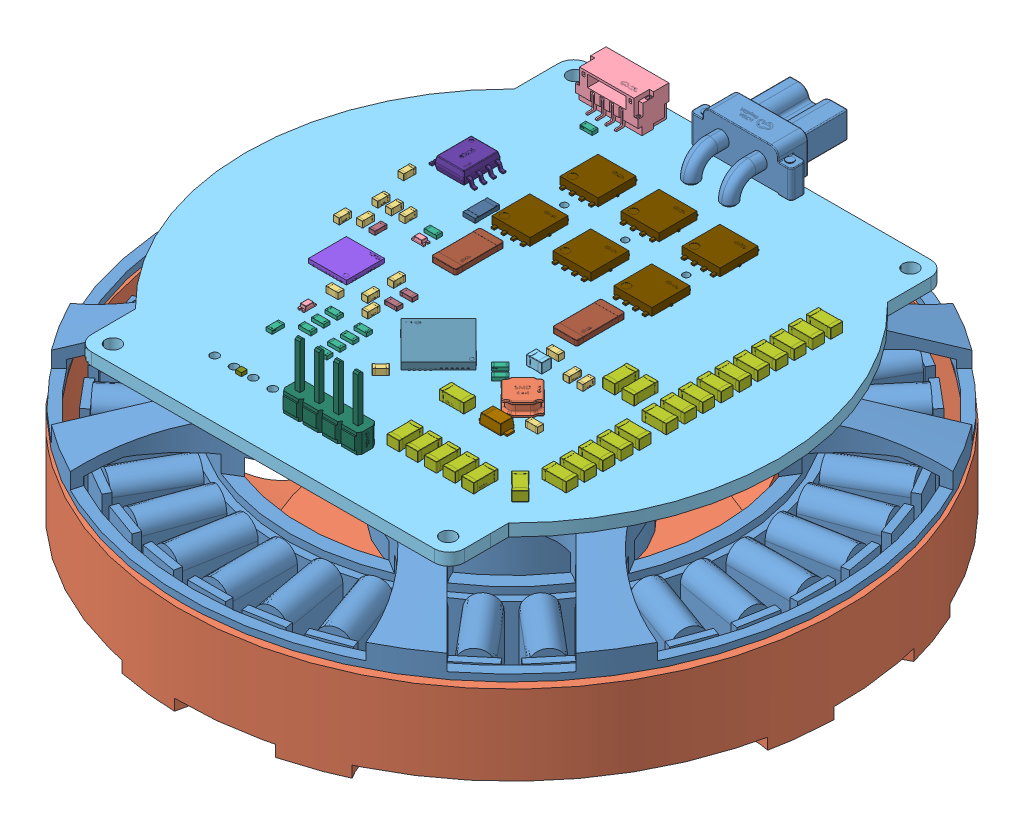
SolidWorks assembly 8108_brushless, configuration Default. Lengths in mm.
Overall size (121.93 40.03 121.93).
306 component instances, 23 part files, 3 mates.
Components (placement in the parent):
- 8108_roter-1: 8108_roter [Default] at (32.6545 40.9666 69.698) size (86.5 19.3 86.5)
- 8108_magnet shaft-1: 8108_magnet shaft [Default] at (32.6545 40.2666 69.698) x (-0.784297 0 -0.620385) z (-0.620385 0 0.784297) size (86.8 25.3 86.8)
- bldc_controller_board.step-1: bldc_controller_board.step [Default] at (32.6609 51.6569 69.7006) x (0.999996 0 -0.002863) z (0 1 0) size (69.98 72.92 11.54)
  - MX0O-C1.step-1: MX0O-C1.step [Default] at (-12.954 -10.287 1.6001) size (1.6 0.8 0.8)
    - C0603.step-1: C0603.step [Default] at origin size (1.6 0.8 0.8)
      - SOLID.step-1: SOLID.step [Default] at origin size (1.6 0.8 0.8)
  - MX0O-C2.step-1: MX0O-C2.step [Default] at (-20.955 -1.27 1.6001) x (0 -1 0) z (0 0 1) size (1.6 0.8 0.8)
    - C0603.step-1: C0603.step [Default] at origin size (1.6 0.8 0.8)
      - SOLID.step-1: SOLID.step [Default] at origin size (1.6 0.8 0.8)
  - MX0O-C8.step-1: MX0O-C8.step [Default] at (8.636 -2.921 1.6001) size (1.6 0.8 0.8)
    - C0603.step-1: C0603.step [Default] at origin size (1.6 0.8 0.8)
      - SOLID.step-1: SOLID.step [Default] at origin size (1.6 0.8 0.8)
  - MX0O-C9.step-1: MX0O-C9.step [Default] at (-8.382 -10.16 1.6001) x (0 -1 0) z (0 0 1) size (1.6 0.8 0.8)
    - C0603.step-1: C0603.step [Default] at origin size (1.6 0.8 0.8)
      - SOLID.step-1: SOLID.step [Default] at origin size (1.6 0.8 0.8)
  - MX0O-C10.step-1: MX0O-C10.step [Default] at (-1.016 -16.256 1.6001) x (0.707107 0.707107 0) z (0 0 1) size (1.6 0.8 0.8)
    - C0603.step-1: C0603.step [Default] at origin size (1.6 0.8 0.8)
      - SOLID.step-1: SOLID.step [Default] at origin size (1.6 0.8 0.8)
  - MX0O-C12.step-1: MX0O-C12.step [Default] at (15.494 -12.573 1.6001) size (1.6 0.8 0.8)
    - C0603.step-1: C0603.step [Default] at origin size (1.6 0.8 0.8)
      - SOLID.step-1: SOLID.step [Default] at origin size (1.6 0.8 0.8)
  - MX0O-C13.step-1: MX0O-C13.step [Default] at (12.239 -4.312 1.6001) x (0 -1 0) z (0 0 1) size (1.6 0.8 0.8)
    - C0603.step-1: C0603.step [Default] at origin size (1.6 0.8 0.8)
      - SOLID.step-1: SOLID.step [Default] at origin size (1.6 0.8 0.8)
  - MX0O-C14.step-1: MX0O-C14.step [Default] at (14.035 -4.3125 1.6001) x (0 -1 0) z (0 0 1) size (1.6 0.8 0.8)
    - C0603.step-1: C0603.step [Default] at origin size (1.6 0.8 0.8)
      - SOLID.step-1: SOLID.step [Default] at origin size (1.6 0.8 0.8)
  - MX0O-C55.step-1: MX0O-C55.step [Default] at (-21.717 8.001 1.6001) x (0 1 0) z (0 0 1) size (1.6 0.8 0.8)
    - C0603.step-1: C0603.step [Default] at origin size (1.6 0.8 0.8)
      - SOLID.step-1: SOLID.step [Default] at origin size (1.6 0.8 0.8)
  - MX0O-U11.step-1: MX0O-U11.step [Default] at (-18.542 3.175 1.6001) x (0 1 0) z (0 0 1) size (1.6 0.8 0.8)
    - C0603.step-1: C0603.step [Default] at origin size (1.6 0.8 0.8)
      - SOLID.step-1: SOLID.step [Default] at origin size (1.6 0.8 0.8)
  - MX0O-U12.step-1: MX0O-U12.step [Default] at (-16.764 3.175 1.6001) x (0 -1 0) z (0 0 1) size (1.6 0.8 0.8)
    - C0603.step-1: C0603.step [Default] at origin size (1.6 0.8 0.8)
      - SOLID.step-1: SOLID.step [Default] at origin size (1.6 0.8 0.8)
  - MX0O-C57.step-1: MX0O-C57.step [Default] at (-10.16 -8.382 1.6001) x (0 -1 0) z (0 0 1) size (1.6 0.8 0.8)
    - C0603.step-1: C0603.step [Default] at origin size (1.6 0.8 0.8)
      - SOLID.step-1: SOLID.step [Default] at origin size (1.6 0.8 0.8)
  - MX0O-C58.step-1: MX0O-C58.step [Default] at (-10.16 -4.953 1.6001) x (0 -1 0) z (0 0 1) size (1.6 0.8 0.8)
    - C0603.step-1: C0603.step [Default] at origin size (1.6 0.8 0.8)
      - SOLID.step-1: SOLID.step [Default] at origin size (1.6 0.8 0.8)
  - MX0O-C56.step-1: MX0O-C56.step [Default] at (-20.32 3.175 1.6001) x (0 -1 0) z (0 0 1) size (1.6 0.8 0.8)
    - C0603.step-1: C0603.step [Default] at origin size (1.6 0.8 0.8)
      - SOLID.step-1: SOLID.step [Default] at origin size (1.6 0.8 0.8)
  - MX0O-U10.step-1: MX0O-U10.step [Default] at (-19.072 -0.1121 1.6001) x (0 1 0) z (0 0 1) size (1.6 0.8 0.8)
    - C0603.step-1: C0603.step [Default] at origin size (1.6 0.8 0.8)
      - SOLID.step-1: SOLID.step [Default] at origin size (1.6 0.8 0.8)
  - MX0O-LED2.step-1: MX0O-LED2.step [Default] at (-13.335 -13.589 1.6001) x (0 1 0) z (0 0 1) size (1.62 0.82 0.56)
    - LED0603-RD.step-1: LED0603-RD.step [Default] at origin size (1.62 0.82 0.56)
      - COMPOUND.step-1: COMPOUND.step [Default] at origin size (1.62 0.82 0.56)
  - MX0O-LED1.step-1: MX0O-LED1.step [Default] at (-13.335 1.397 1.6001) size (1.62 0.82 0.56)
    - LED0603-RD.step-1: LED0603-RD.step [Default] at origin size (1.62 0.82 0.56)
      - COMPOUND.step-1: COMPOUND.step [Default] at origin size (1.62 0.82 0.56)
  - MX0O-C5.step-1: MX0O-C5.step [Default] at (8.763 -5.207 1.6001) size (2 1.3 1.3)
    - C0805.step-1: C0805.step [Default] at origin size (2 1.3 1.3)
      - SOLID-0.step-1: SOLID-0.step [Default] at origin size (2 1.3 1.3)
  - MX0O-R4.step-1: MX0O-R4.step [Default] at (-13.3265 3.066 1.6001) x (-1 0 0) z (0 0 1) size (1.62 0.81 0.45)
    - R0603.step-1: R0603.step [Default] at origin size (1.62 0.81 0.45)
      - COMPOUND-1.step-1: COMPOUND-1.step [Default] at origin size (1.62 0.81 0.45)
  - MX0O-R7.step-1: MX0O-R7.step [Default] at (-10.668 -14.478 1.6001) x (-1 0 0) z (0 0 1) size (1.62 0.81 0.45)
    - R0603.step-1: R0603.step [Default] at origin size (1.62 0.81 0.45)
      - COMPOUND-1.step-1: COMPOUND-1.step [Default] at origin size (1.62 0.81 0.45)
  - MX0O-R8.step-1: MX0O-R8.step [Default] at (-10.668 -12.7 1.6001) x (-1 0 0) z (0 0 1) size (1.62 0.81 0.45)
    - R0603.step-1: R0603.step [Default] at origin size (1.62 0.81 0.45)
      - COMPOUND-1.step-1: COMPOUND-1.step [Default] at origin size (1.62 0.81 0.45)
  - MX0O-R9.step-1: MX0O-R9.step [Default] at (-6.858 -12.7 1.6001) x (-1 0 0) z (0 0 1) size (1.62 0.81 0.45)
    - R0603.step-1: R0603.step [Default] at origin size (1.62 0.81 0.45)
      - COMPOUND-1.step-1: COMPOUND-1.step [Default] at origin size (1.62 0.81 0.45)
  - MX0O-R10.step-1: MX0O-R10.step [Default] at (-6.858 -17.907 1.6001) x (-1 0 0) z (0 0 1) size (1.62 0.81 0.45)
    - R0603.step-1: R0603.step [Default] at origin size (1.62 0.81 0.45)
      - COMPOUND-1.step-1: COMPOUND-1.step [Default] at origin size (1.62 0.81 0.45)
  - MX0O-R11.step-1: MX0O-R11.step [Default] at (-6.8544 -16.1801 1.6001) x (-1 0 0) z (0 0 1) size (1.62 0.81 0.45)
    - R0603.step-1: R0603.step [Default] at origin size (1.62 0.81 0.45)
      - COMPOUND-1.step-1: COMPOUND-1.step [Default] at origin size (1.62 0.81 0.45)
  - MX0O-R12.step-1: MX0O-R12.step [Default] at (-6.8544 -14.4682 1.6001) x (-1 0 0) z (0 0 1) size (1.62 0.81 0.45)
    - R0603.step-1: R0603.step [Default] at origin size (1.62 0.81 0.45)
      - COMPOUND-1.step-1: COMPOUND-1.step [Default] at origin size (1.62 0.81 0.45)
  - MX0O-R13.step-1: MX0O-R13.step [Default] at (7.493 -9.017 1.6001) x (-0.707107 -0.707107 0) z (0 0 1) size (1.62 0.81 0.45)
    - R0603.step-1: R0603.step [Default] at origin size (1.62 0.81 0.45)
      - COMPOUND-1.step-1: COMPOUND-1.step [Default] at origin size (1.62 0.81 0.45)
  - MX0O-R14.step-1: MX0O-R14.step [Default] at (6.35 -7.874 1.6001) x (0.707107 0.707107 0) z (0 0 1) size (1.62 0.81 0.45)
    - R0603.step-1: R0603.step [Default] at origin size (1.62 0.81 0.45)
      - COMPOUND-1.step-1: COMPOUND-1.step [Default] at origin size (1.62 0.81 0.45)
  - MX0O-R16.step-1: MX0O-R16.step [Default] at (-14.859 25.1461 1.6001) size (1.62 0.81 0.45)
    - R0603.step-1: R0603.step [Default] at origin size (1.62 0.81 0.45)
      - COMPOUND-1.step-1: COMPOUND-1.step [Default] at origin size (1.62 0.81 0.45)
  - MX0O-R17.step-1: MX0O-R17.step [Default] at (-10.6407 -16.2102 1.6001) x (-1 0 0) z (0 0 1) size (1.62 0.81 0.45)
    - R0603.step-1: R0603.step [Default] at origin size (1.62 0.81 0.45)
      - COMPOUND-1.step-1: COMPOUND-1.step [Default] at origin size (1.62 0.81 0.45)
  - MX0O-R18.step-1: MX0O-R18.step [Default] at (-12.954 -18.161 1.6001) x (0 1 0) z (0 0 1) size (1.62 0.81 0.45)
    - R0603.step-1: R0603.step [Default] at origin size (1.62 0.81 0.45)
      - COMPOUND-1.step-1: COMPOUND-1.step [Default] at origin size (1.62 0.81 0.45)
  - MX0O-R1.step-1: MX0O-R1.step [Default] at (-2.032 -3.81 0) x (-1 0 0) z (0 0 -1) size (1.62 0.81 0.45)
    - R0603.step-1: R0603.step [Default] at origin size (1.62 0.81 0.45)
      - COMPOUND-1.step-1: COMPOUND-1.step [Default] at origin size (1.62 0.81 0.45)
  - MX0O-C7.step-1: MX0O-C7.step [Default] at (16.1632 -1.8521 1.6001) x (0 1 0) z (0 0 1) size (3.2 1.6 1.3)
    - C1206.step-1: C1206.step [Default] at origin size (3.2 1.6 1.3)
      - SOLID-2.step-1: SOLID-2.step [Default] at origin size (3.2 1.6 1.3)
  - MX0O-C11.step-1: MX0O-C11.step [Default] at (7.555 -14.7294 1.6001) x (-1 0 0) z (0 0 1) size (3.2 1.6 1.3)
    - C1206.step-1: C1206.step [Default] at origin size (3.2 1.6 1.3)
      - SOLID-2.step-1: SOLID-2.step [Default] at origin size (3.2 1.6 1.3)
  - MX0O-C15.step-1: MX0O-C15.step [Default] at (21.717 -20.701 1.6001) x (0.707107 -0.707107 0) z (0 0 1) size (3.2 1.6 1.3)
    - C1206.step-1: C1206.step [Default] at origin size (3.2 1.6 1.3)
      - SOLID-2.step-1: SOLID-2.step [Default] at origin size (3.2 1.6 1.3)
  - MX0O-C16.step-1: MX0O-C16.step [Default] at (23.281 15.479 0) x (1 0 0) z (0 0 -1) size (3.2 1.6 1.3)
    - C1206.step-1: C1206.step [Default] at origin size (3.2 1.6 1.3)
      - SOLID-2.step-1: SOLID-2.step [Default] at origin size (3.2 1.6 1.3)
  - MX0O-C17.step-1: MX0O-C17.step [Default] at (12.065 20.828 0) x (-1 0 0) z (0 0 -1) size (3.2 1.6 1.3)
    - C1206.step-1: C1206.step [Default] at origin size (3.2 1.6 1.3)
      - SOLID-2.step-1: SOLID-2.step [Default] at origin size (3.2 1.6 1.3)
  - MX0O-C18.step-1: MX0O-C18.step [Default] at (11.8235 -22.3795 0) x (0 -1 0) z (0 0 -1) size (3.2 1.6 1.3)
    - C1206.step-1: C1206.step [Default] at origin size (3.2 1.6 1.3)
      - SOLID-2.step-1: SOLID-2.step [Default] at origin size (3.2 1.6 1.3)
  - MX0O-C19.step-1: MX0O-C19.step [Default] at (16.6495 -22.3795 0) x (0 -1 0) z (0 0 -1) size (3.2 1.6 1.3)
    - C1206.step-1: C1206.step [Default] at origin size (3.2 1.6 1.3)
      - SOLID-2.step-1: SOLID-2.step [Default] at origin size (3.2 1.6 1.3)
  - MX0O-C20.step-1: MX0O-C20.step [Default] at (8.382 -22.479 1.6001) x (0 -1 0) z (0 0 1) size (3.2 1.6 1.3)
    - C1206.step-1: C1206.step [Default] at origin size (3.2 1.6 1.3)
      - SOLID-2.step-1: SOLID-2.step [Default] at origin size (3.2 1.6 1.3)
  - MX0O-C21.step-1: MX0O-C21.step [Default] at (23.281 -14.62 1.6001) size (3.2 1.6 1.3)
    - C1206.step-1: C1206.step [Default] at origin size (3.2 1.6 1.3)
      - SOLID-2.step-1: SOLID-2.step [Default] at origin size (3.2 1.6 1.3)
  - MX0O-C22.step-1: MX0O-C22.step [Default] at (23.281 17.892 1.6001) size (3.2 1.6 1.3)
    - C1206.step-1: C1206.step [Default] at origin size (3.2 1.6 1.3)
      - SOLID-2.step-1: SOLID-2.step [Default] at origin size (3.2 1.6 1.3)
  - MX0O-C23.step-1: MX0O-C23.step [Default] at (23.281 -13.477 0) x (1 0 0) z (0 0 -1) size (3.2 1.6 1.3)
    - C1206.step-1: C1206.step [Default] at origin size (3.2 1.6 1.3)
      - SOLID-2.step-1: SOLID-2.step [Default] at origin size (3.2 1.6 1.3)
  - MX0O-C24.step-1: MX0O-C24.step [Default] at (23.281 -11.064 0) x (1 0 0) z (0 0 -1) size (3.2 1.6 1.3)
    - C1206.step-1: C1206.step [Default] at origin size (3.2 1.6 1.3)
      - SOLID-2.step-1: SOLID-2.step [Default] at origin size (3.2 1.6 1.3)
  - MX0O-C25.step-1: MX0O-C25.step [Default] at (23.281 -3.825 0) x (1 0 0) z (0 0 -1) size (3.2 1.6 1.3)
    - C1206.step-1: C1206.step [Default] at origin size (3.2 1.6 1.3)
      - SOLID-2.step-1: SOLID-2.step [Default] at origin size (3.2 1.6 1.3)
  - MX0O-C26.step-1: MX0O-C26.step [Default] at (23.281 -1.412 0) x (1 0 0) z (0 0 -1) size (3.2 1.6 1.3)
    - C1206.step-1: C1206.step [Default] at origin size (3.2 1.6 1.3)
      - SOLID-2.step-1: SOLID-2.step [Default] at origin size (3.2 1.6 1.3)
  - MX0O-C27.step-1: MX0O-C27.step [Default] at (23.281 3.414 0) x (1 0 0) z (0 0 -1) size (3.2 1.6 1.3)
    - C1206.step-1: C1206.step [Default] at origin size (3.2 1.6 1.3)
      - SOLID-2.step-1: SOLID-2.step [Default] at origin size (3.2 1.6 1.3)
  - MX0O-C28.step-1: MX0O-C28.step [Default] at (23.281 8.24 0) x (1 0 0) z (0 0 -1) size (3.2 1.6 1.3)
    - C1206.step-1: C1206.step [Default] at origin size (3.2 1.6 1.3)
      - SOLID-2.step-1: SOLID-2.step [Default] at origin size (3.2 1.6 1.3)
  - MX0O-C29.step-1: MX0O-C29.step [Default] at (23.281 15.479 1.6001) size (3.2 1.6 1.3)
    - C1206.step-1: C1206.step [Default] at origin size (3.2 1.6 1.3)
      - SOLID-2.step-1: SOLID-2.step [Default] at origin size (3.2 1.6 1.3)
  - MX0O-C30.step-1: MX0O-C30.step [Default] at (23.281 10.653 1.6001) size (3.2 1.6 1.3)
    - C1206.step-1: C1206.step [Default] at origin size (3.2 1.6 1.3)
      - SOLID-2.step-1: SOLID-2.step [Default] at origin size (3.2 1.6 1.3)
  - MX0O-C31.step-1: MX0O-C31.step [Default] at (23.281 5.827 1.6001) size (3.2 1.6 1.3)
    - C1206.step-1: C1206.step [Default] at origin size (3.2 1.6 1.3)
      - SOLID-2.step-1: SOLID-2.step [Default] at origin size (3.2 1.6 1.3)
  - MX0O-C32.step-1: MX0O-C32.step [Default] at (23.281 1.001 1.6001) size (3.2 1.6 1.3)
    - C1206.step-1: C1206.step [Default] at origin size (3.2 1.6 1.3)
      - SOLID-2.step-1: SOLID-2.step [Default] at origin size (3.2 1.6 1.3)
  - MX0O-C33.step-1: MX0O-C33.step [Default] at (23.281 -3.825 1.6001) size (3.2 1.6 1.3)
    - C1206.step-1: C1206.step [Default] at origin size (3.2 1.6 1.3)
      - SOLID-2.step-1: SOLID-2.step [Default] at origin size (3.2 1.6 1.3)
  - MX0O-C34.step-1: MX0O-C34.step [Default] at (23.281 -9.794 1.6001) size (3.2 1.6 1.3)
    - C1206.step-1: C1206.step [Default] at origin size (3.2 1.6 1.3)
      - SOLID-2.step-1: SOLID-2.step [Default] at origin size (3.2 1.6 1.3)
  - MX0O-C35.step-1: MX0O-C35.step [Default] at (23.281 13.066 0) x (1 0 0) z (0 0 -1) size (3.2 1.6 1.3)
    - C1206.step-1: C1206.step [Default] at origin size (3.2 1.6 1.3)
      - SOLID-2.step-1: SOLID-2.step [Default] at origin size (3.2 1.6 1.3)
  - MX0O-C36.step-1: MX0O-C36.step [Default] at (23.281 17.892 0) x (1 0 0) z (0 0 -1) size (3.2 1.6 1.3)
    - C1206.step-1: C1206.step [Default] at origin size (3.2 1.6 1.3)
      - SOLID-2.step-1: SOLID-2.step [Default] at origin size (3.2 1.6 1.3)
  - MX0O-C37.step-1: MX0O-C37.step [Default] at (9.4105 -22.3795 0) x (0 -1 0) z (0 0 -1) size (3.2 1.6 1.3)
    - C1206.step-1: C1206.step [Default] at origin size (3.2 1.6 1.3)
      - SOLID-2.step-1: SOLID-2.step [Default] at origin size (3.2 1.6 1.3)
  - MX0O-C38.step-1: MX0O-C38.step [Default] at (14.2365 -22.3795 0) x (0 -1 0) z (0 0 -1) size (3.2 1.6 1.3)
    - C1206.step-1: C1206.step [Default] at origin size (3.2 1.6 1.3)
      - SOLID-2.step-1: SOLID-2.step [Default] at origin size (3.2 1.6 1.3)
  - MX0O-C39.step-1: MX0O-C39.step [Default] at (19.0625 -22.3795 0) x (0 -1 0) z (0 0 -1) size (3.2 1.6 1.3)
    - C1206.step-1: C1206.step [Default] at origin size (3.2 1.6 1.3)
      - SOLID-2.step-1: SOLID-2.step [Default] at origin size (3.2 1.6 1.3)
  - MX0O-C40.step-1: MX0O-C40.step [Default] at (23.281 20.32 0) x (1 0 0) z (0 0 -1) size (3.2 1.6 1.3)
    - C1206.step-1: C1206.step [Default] at origin size (3.2 1.6 1.3)
      - SOLID-2.step-1: SOLID-2.step [Default] at origin size (3.2 1.6 1.3)
  - MX0O-C41.step-1: MX0O-C41.step [Default] at (23.281 -17.033 1.6001) size (3.2 1.6 1.3)
    - C1206.step-1: C1206.step [Default] at origin size (3.2 1.6 1.3)
      - SOLID-2.step-1: SOLID-2.step [Default] at origin size (3.2 1.6 1.3)
  - MX0O-C42.step-1: MX0O-C42.step [Default] at (23.281 -18.303 0) x (1 0 0) z (0 0 -1) size (3.2 1.6 1.3)
    - C1206.step-1: C1206.step [Default] at origin size (3.2 1.6 1.3)
      - SOLID-2.step-1: SOLID-2.step [Default] at origin size (3.2 1.6 1.3)
  - MX0O-C43.step-1: MX0O-C43.step [Default] at (23.281 -15.89 0) x (1 0 0) z (0 0 -1) size (3.2 1.6 1.3)
    - C1206.step-1: C1206.step [Default] at origin size (3.2 1.6 1.3)
      - SOLID-2.step-1: SOLID-2.step [Default] at origin size (3.2 1.6 1.3)
  - MX0O-C44.step-1: MX0O-C44.step [Default] at (23.281 -8.651 0) x (1 0 0) z (0 0 -1) size (3.2 1.6 1.3)
    - C1206.step-1: C1206.step [Default] at origin size (3.2 1.6 1.3)
      - SOLID-2.step-1: SOLID-2.step [Default] at origin size (3.2 1.6 1.3)
  - MX0O-C45.step-1: MX0O-C45.step [Default] at (23.281 -6.238 0) x (1 0 0) z (0 0 -1) size (3.2 1.6 1.3)
    - C1206.step-1: C1206.step [Default] at origin size (3.2 1.6 1.3)
      - SOLID-2.step-1: SOLID-2.step [Default] at origin size (3.2 1.6 1.3)
  - MX0O-C46.step-1: MX0O-C46.step [Default] at (23.281 1.001 0) x (1 0 0) z (0 0 -1) size (3.2 1.6 1.3)
    - C1206.step-1: C1206.step [Default] at origin size (3.2 1.6 1.3)
      - SOLID-2.step-1: SOLID-2.step [Default] at origin size (3.2 1.6 1.3)
  - MX0O-C47.step-1: MX0O-C47.step [Default] at (23.281 5.827 0) x (1 0 0) z (0 0 -1) size (3.2 1.6 1.3)
    - C1206.step-1: C1206.step [Default] at origin size (3.2 1.6 1.3)
      - SOLID-2.step-1: SOLID-2.step [Default] at origin size (3.2 1.6 1.3)
  - MX0O-C48.step-1: MX0O-C48.step [Default] at (23.281 10.638 0) x (1 0 0) z (0 0 -1) size (3.2 1.6 1.3)
    - C1206.step-1: C1206.step [Default] at origin size (3.2 1.6 1.3)
      - SOLID-2.step-1: SOLID-2.step [Default] at origin size (3.2 1.6 1.3)
  - MX0O-C49.step-1: MX0O-C49.step [Default] at (23.281 13.066 1.6001) size (3.2 1.6 1.3)
    - C1206.step-1: C1206.step [Default] at origin size (3.2 1.6 1.3)
      - SOLID-2.step-1: SOLID-2.step [Default] at origin size (3.2 1.6 1.3)
  - MX0O-C50.step-1: MX0O-C50.step [Default] at (23.281 8.24 1.6001) size (3.2 1.6 1.3)
    - C1206.step-1: C1206.step [Default] at origin size (3.2 1.6 1.3)
      - SOLID-2.step-1: SOLID-2.step [Default] at origin size (3.2 1.6 1.3)
  - MX0O-C51.step-1: MX0O-C51.step [Default] at (23.281 3.414 1.6001) size (3.2 1.6 1.3)
    - C1206.step-1: C1206.step [Default] at origin size (3.2 1.6 1.3)
      - SOLID-2.step-1: SOLID-2.step [Default] at origin size (3.2 1.6 1.3)
  - MX0O-C52.step-1: MX0O-C52.step [Default] at (23.281 -1.412 1.6001) size (3.2 1.6 1.3)
    - C1206.step-1: C1206.step [Default] at origin size (3.2 1.6 1.3)
      - SOLID-2.step-1: SOLID-2.step [Default] at origin size (3.2 1.6 1.3)
  - MX0O-C53.step-1: MX0O-C53.step [Default] at (23.281 -7.381 1.6001) size (3.2 1.6 1.3)
    - C1206.step-1: C1206.step [Default] at origin size (3.2 1.6 1.3)
      - SOLID-2.step-1: SOLID-2.step [Default] at origin size (3.2 1.6 1.3)
  - MX0O-C54.step-1: MX0O-C54.step [Default] at (23.281 -12.192 1.6001) size (3.2 1.6 1.3)
    - C1206.step-1: C1206.step [Default] at origin size (3.2 1.6 1.3)
      - SOLID-2.step-1: SOLID-2.step [Default] at origin size (3.2 1.6 1.3)
  - MX0O-C60.step-1: MX0O-C60.step [Default] at (13.2789 -22.4774 1.6001) x (0 -1 0) z (0 0 1) size (3.2 1.6 1.3)
    - C1206.step-1: C1206.step [Default] at origin size (3.2 1.6 1.3)
      - SOLID-2.step-1: SOLID-2.step [Default] at origin size (3.2 1.6 1.3)
  - MX0O-C61.step-1: MX0O-C61.step [Default] at (10.8223 -22.4774 1.6001) x (0 -1 0) z (0 0 1) size (3.2 1.6 1.3)
    - C1206.step-1: C1206.step [Default] at origin size (3.2 1.6 1.3)
      - SOLID-2.step-1: SOLID-2.step [Default] at origin size (3.2 1.6 1.3)
  - MX0O-C62.step-1: MX0O-C62.step [Default] at (18.1049 -22.4149 1.6001) x (0 -1 0) z (0 0 1) size (3.2 1.6 1.3)
    - C1206.step-1: C1206.step [Default] at origin size (3.2 1.6 1.3)
      - SOLID-2.step-1: SOLID-2.step [Default] at origin size (3.2 1.6 1.3)
  - MX0O-C63.step-1: MX0O-C63.step [Default] at (15.6483 -22.4149 1.6001) x (0 -1 0) z (0 0 1) size (3.2 1.6 1.3)
    - C1206.step-1: C1206.step [Default] at origin size (3.2 1.6 1.3)
      - SOLID-2.step-1: SOLID-2.step [Default] at origin size (3.2 1.6 1.3)
  - MX0O-C6.step-1: MX0O-C6.step [Default] at (18.7032 -1.8521 1.6001) x (0 1 0) z (0 0 1) size (3.2 1.6 1.3)
    - C1206.step-1: C1206.step [Default] at origin size (3.2 1.6 1.3)
      - SOLID-2.step-1: SOLID-2.step [Default] at origin size (3.2 1.6 1.3)
  - MX0O-U1.step-1: MX0O-U1.step [Default] at (-15.748 -5.969 1.6001) x (-1 0 0) z (0 0 1) size (5.02 5.02 0.58)
    - UFQFPN-32_L5.0-W5.0-P0.50-TL-1.step-1: UFQFPN-32_L5.0-W5.0-P0.50-TL-1.step [Default] at origin size (5.02 5.02 0.58)
      - SOLID-3.step-1: SOLID-3.step [Default] at origin size (5.02 5.02 0.58)
  - MX0O-D1.step-1: MX0O-D1.step [Default] at (12.7 -14.732 1.6001) size (3.7 1.8 1.31)
    - SOD-123F_L2.8-W1.8-LS3.7-RD.step-1: SOD-123F_L2.8-W1.8-LS3.7-RD.step [Default] at origin size (3.7 1.8 1.31)
      - SOLID-4.step-1: SOLID-4.step [Default] at origin size (3.7 1.8 1.31)
  - MX0O-R15.step-1: MX0O-R15.step [Default] at (-12.573 8.636 1.6001) x (0 1 0) z (0 0 1) size (3.2 1.6 0.56)
    - R1206.step-1: R1206.step [Default] at origin size (3.2 1.6 0.56)
      - COMPOUND-5.step-1: COMPOUND-5.step [Default] at origin size (3.2 1.6 0.56)
  - MX0O-R6.step-1: MX0O-R6.step [Default] at (-8.7049 2.9645 1.6001) x (0 1 0) z (0 0 1) size (6.43 3.23 0.72)
    - RES-SMD_L6.4-W3.2-R2512.step-1: RES-SMD_L6.4-W3.2-R2512.step [Default] at origin size (6.43 3.23 0.72)
      - SOLID-6.step-1: SOLID-6.step [Default] at origin size (6.43 3.23 0.72)
  - MX0O-R5.step-1: MX0O-R5.step [Default] at (7.342 2.794 1.6001) x (0 1 0) z (0 0 1) size (6.43 3.23 0.72)
    - RES-SMD_L6.4-W3.2-R2512.step-1: RES-SMD_L6.4-W3.2-R2512.step [Default] at origin size (6.43 3.23 0.72)
      - SOLID-6.step-1: SOLID-6.step [Default] at origin size (6.43 3.23 0.72)
  - MX0O-C59.step-1: MX0O-C59.step [Default] at (0.889 -3.81 0) x (-1 0 0) z (0 0 -1) size (1 0.5 0.5)
    - C0402.step-1: C0402.step [Default] at origin size (1 0.5 0.5)
      - SOLID-7.step-1: SOLID-7.step [Default] at origin size (1 0.5 0.5)
  - MX0O-U14.step-1: MX0O-U14.step [Default] at (-7.747 -7.747 1.6001) x (-1 0 0) z (0 0 1) size (1.6 0.8 0.5)
    - L0603.step-1: L0603.step [Default] at origin size (1.6 0.8 0.5)
      - SOLID-8.step-1: SOLID-8.step [Default] at origin size (1.6 0.8 0.5)
  - MX0O-U15.step-1: MX0O-U15.step [Default] at (-7.747 -5.715 1.6001) x (-1 0 0) z (0 0 1) size (1.6 0.8 0.5)
    - L0603.step-1: L0603.step [Default] at origin size (1.6 0.8 0.5)
      - SOLID-8.step-1: SOLID-8.step [Default] at origin size (1.6 0.8 0.5)
  - MX0O-U13.step-1: MX0O-U13.step [Default] at (-17.421 -0.1325 1.6001) x (0 -1 0) z (0 0 1) size (1.6 0.8 0.5)
    - L0603.step-1: L0603.step [Default] at origin size (1.6 0.8 0.5)
      - SOLID-8.step-1: SOLID-8.step [Default] at origin size (1.6 0.8 0.5)
  - MX0O-U2.step-1: MX0O-U2.step [Default] at (0 -9.652 1.6001) x (-0.707107 -0.707107 0) z (0 0 1) size (7.02 7.02 0.92)
    - VQFN-48_L7.0-W7.0-P0.50-TL-EP5.1.step-1: VQFN-48_L7.0-W7.0-P0.50-TL-EP5.1.step [Default] at origin size (7.02 7.02 0.92)
      - COMPOUND-9.step-1: COMPOUND-9.step [Default] at origin size (7.02 7.02 0.92)
  - MX0O-H2.step-1: MX0O-H2.step [Default] at (1.905 -26.0351 1.6001) size (10.17 2.66 11.54)
    - HDR-TH_4P-P2.54-V-M.step-1: HDR-TH_4P-P2.54-V-M.step [Default] at origin size (10.17 2.66 11.54)
      - SOLID-10.step-1: SOLID-10.step [Default] at origin size (10.17 2.66 11.54)
  - MX0O-U20.step-1: MX0O-U20.step [Default] at (-10.16 -25.1461 1.6001) size (0.76 0.76 0.76)
    - CONN-TH_B4B-EH-A-LF-SN.step-1: CONN-TH_B4B-EH-A-LF-SN.step [Default] at origin size (0.76 0.76 0.76)
  - MX0O-U3.step-1: MX0O-U3.step [Default] at (-18.542 12.827 1.6001) x (0 -1 0) z (0 0 1) size (4.81 6 1.72)
    - SOIC-8_L4.9-W3.9-P1.27-LS6.0-BL.step-1: SOIC-8_L4.9-W3.9-P1.27-LS6.0-BL.step [Default] at origin size (4.81 6 1.72)
      - COMPOUND-11.step-1: COMPOUND-11.step [Default] at origin size (4.81 6 1.72)
  - MX0O-U5.step-1: MX0O-U5.step [Default] at (8 10.5 1.6001) size (5.3 6 1.01)
    - POWERVDFN-8_L5.0-W5.0-P1.27-LS6.0-BL.step-1: POWERVDFN-8_L5.0-W5.0-P1.27-LS6.0-BL.step [Default] at origin size (5.3 6 1.01)
      - SOLID-12.step-1: SOLID-12.step [Default] at origin size (5.3 6 1.01)
  - MX0O-U6.step-1: MX0O-U6.step [Default] at (0 19.5 1.6001) size (5.3 6 1.01)
    - POWERVDFN-8_L5.0-W5.0-P1.27-LS6.0-BL.step-1: POWERVDFN-8_L5.0-W5.0-P1.27-LS6.0-BL.step [Default] at origin size (5.3 6 1.01)
      - SOLID-12.step-1: SOLID-12.step [Default] at origin size (5.3 6 1.01)
  - MX0O-U7.step-1: MX0O-U7.step [Default] at (0 10.5 1.6001) size (5.3 6 1.01)
    - POWERVDFN-8_L5.0-W5.0-P1.27-LS6.0-BL.step-1: POWERVDFN-8_L5.0-W5.0-P1.27-LS6.0-BL.step [Default] at origin size (5.3 6 1.01)
      - SOLID-12.step-1: SOLID-12.step [Default] at origin size (5.3 6 1.01)
  - MX0O-U8.step-1: MX0O-U8.step [Default] at (-8 19.5 1.6001) size (5.3 6 1.01)
    - POWERVDFN-8_L5.0-W5.0-P1.27-LS6.0-BL.step-1: POWERVDFN-8_L5.0-W5.0-P1.27-LS6.0-BL.step [Default] at origin size (5.3 6 1.01)
      - SOLID-12.step-1: SOLID-12.step [Default] at origin size (5.3 6 1.01)
  - MX0O-U9.step-1: MX0O-U9.step [Default] at (-8 10.5 1.6001) size (5.3 6 1.01)
    - POWERVDFN-8_L5.0-W5.0-P1.27-LS6.0-BL.step-1: POWERVDFN-8_L5.0-W5.0-P1.27-LS6.0-BL.step [Default] at origin size (5.3 6 1.01)
      - SOLID-12.step-1: SOLID-12.step [Default] at origin size (5.3 6 1.01)
  - MX0O-U4.step-1: MX0O-U4.step [Default] at (8 19.5 1.6001) size (5.3 6 1.01)
    - POWERVDFN-8_L5.0-W5.0-P1.27-LS6.0-BL.step-1: POWERVDFN-8_L5.0-W5.0-P1.27-LS6.0-BL.step [Default] at origin size (5.3 6 1.01)
      - SOLID-12.step-1: SOLID-12.step [Default] at origin size (5.3 6 1.01)
  - MX0O-U19.step-1: MX0O-U19.step [Default] at (0 28.7021 1.6001) x (-1 0 0) z (0 0 1) size (13.3 14.9 7.2)
    - CONN-TH_XT30PW-F-1.step-1: CONN-TH_XT30PW-F-1.step [Default] at origin size (13.3 14.9 7.2)
      - SOLID-13.step-1: SOLID-13.step [Default] at origin size (13.3 14.9 7.2)
  - MX0O-L2.step-1: MX0O-L2.step [Default] at (12.065 -10.668 1.6001) x (0.707107 0.707107 0) z (0 0 1) size (4.02 4 1.87)
    - IND-SMD_L4.0-W4.0.step-1: IND-SMD_L4.0-W4.0.step [Default] at origin size (4.02 4 1.87)
      - SOLID-14.step-1: SOLID-14.step [Default] at origin size (4.02 4 1.87)
  - MX0O-U18.step-1: MX0O-U18.step [Default] x (0 1 0) z (0 0 -1) size (5 6.01 1.1)
    - TSSOP-14_L5.0-W4.4-P0.65-LS6.4-BL.step-1: TSSOP-14_L5.0-W4.4-P0.65-LS6.4-BL.step [Default] at origin size (5 6.01 1.1)
      - COMPOUND-15.step-1: COMPOUND-15.step [Default] at origin size (5 6.01 1.1)
  - MX0O-CN1.step-1: MX0O-CN1.step [Default] at (-14.859 28.7021 1.6001) x (-1 0 0) z (0 0 1) size (8.25 4.86 4.26)
    - CONN-SMD_A1257WR-S-4P.step-1: CONN-SMD_A1257WR-S-4P.step [Default] at origin size (8.25 4.86 4.26)
      - COMPOUND-16.step-1: COMPOUND-16.step [Default] at origin size (8.25 4.86 4.26)
  - Board.step-1: Board.step [Default] at origin size (69.98 65.61 1.6)
Mates (geometry in assembly coordinates):
- Concentric1: concentric anti-aligned: cylinder of 8108_roter-1 through (32.6545 42.4666 69.698) axis (0 -1 0) radius 43.25; cylinder of 8108_magnet shaft-1 through (32.6545 29.7666 69.698) axis (0 1 0) radius 43.4
- Coincident1: coincident anti-aligned: plane of 8108_roter-1 through (32.6545 29.0666 69.698) normal (0 -1 0); plane of 8108_magnet shaft-1 through (32.6545 29.0666 69.698) normal (0 1 0)
- Concentric2: concentric anti-aligned: circle of 8108_roter-1; circle of bldc_controller_board.step-1/Board.step-1
